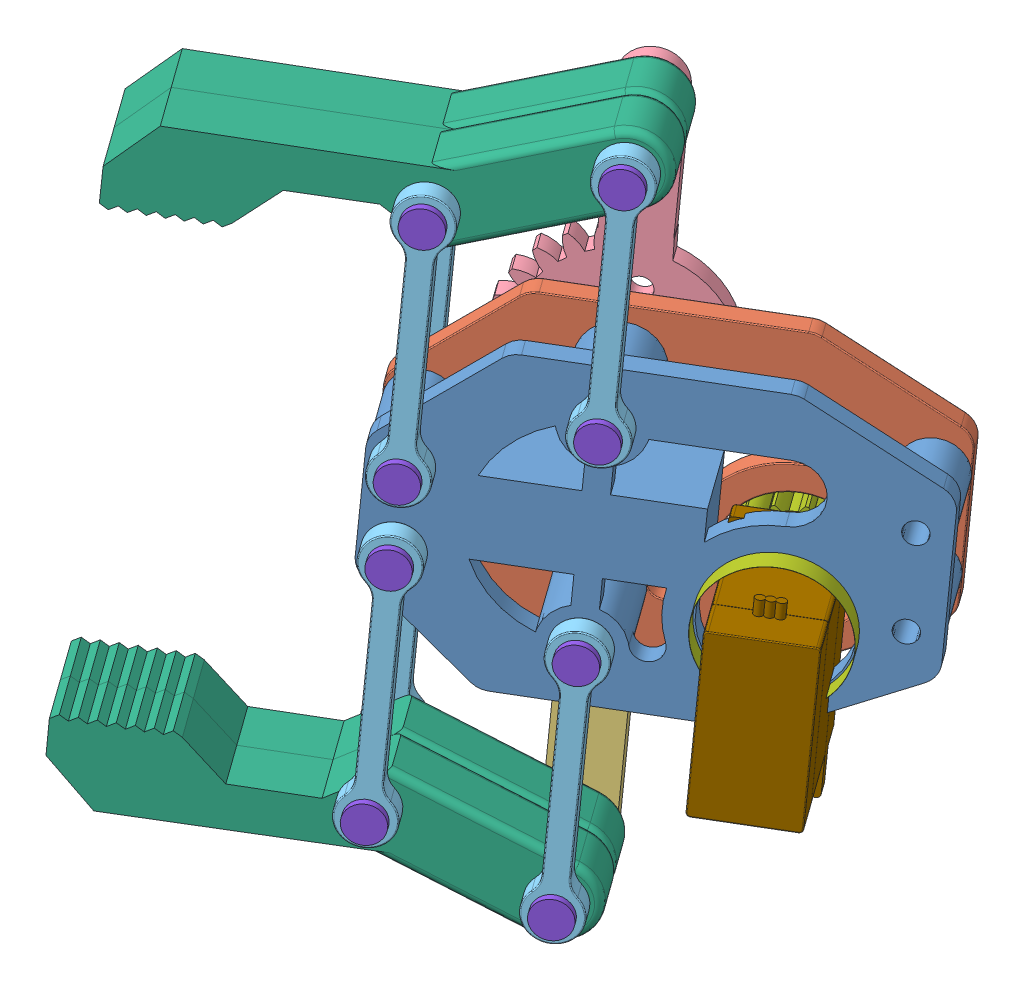
SolidWorks assembly Assemfinal, configuration Default. Lengths in mm.
Overall size (86.17 122.69 75.36).
24 component instances, 9 part files, 63 mates.
Components (placement in the parent):
- Part3-3-3: Part3-3 [Default] at (33.202 8.5379 122.0987) x (-0.009075 -0.994141 0.10771) z (-0.596574 -0.081063 -0.798454) size (41 62 13)
- Part3-3_g-1: Part3-3_g [Default] at (25.536 7.4962 111.8386) x (-0.009075 -0.994141 0.10771) z (-0.596574 -0.081063 -0.798454) size (41 62 3.03)
- part4-4-1: part4-4 [Default] at (-6.5503 -3.4794 133.1692) x (-0.596574 -0.081063 -0.798454) z (0.009075 0.994141 -0.10771) size (3 29.07 49.54)
- part5-5-1: part5-5 [Default] at (-8.095 23.1193 127.8657) x (0.596574 0.081063 0.798454) z (-0.113746 -0.976303 0.184105) size (3 26.63 49.27)
- Part2-2-1: Part2-2 [Default] at (-23.3572 47.3054 138.6922) x (-0.00933 -0.994118 0.107899) z (0.596574 0.081063 0.798454) size (38 7 3)
- Part1-1-1: Part1-1 [Default] at (-1.2513 54.8293 133.3096) x (-0.747201 -0.306991 0.589447) z (-0.596574 -0.081063 -0.798454) size (60.44 20.84 8)
- Part2-2-2: Part2-2 [Default] at (-24.015 -24.7496 146.499) x (0.00882 0.994164 -0.107522) z (0.596574 0.081063 0.798454) size (38 7 3)
- Part1-1-2: Part1-1 [Default] at (-6.8316 -34.2977 136.5082) x (-0.740386 0.439535 0.508564) z (0.596574 0.081063 0.798454) size (60.44 20.84 8)
- Part1-1-3: Part1-1 [Default] at (3.5213 55.4778 139.6973) x (-0.747201 -0.306991 0.589447) z (-0.596574 -0.081063 -0.798454) size (60.44 20.84 8)
- Part1-1-4: Part1-1 [Default] at (-2.059 -33.6492 142.8959) x (-0.740386 0.439535 0.508564) z (0.596574 0.081063 0.798454) size (60.44 20.84 8)
- Part2-2-3: Part2-2 [Default] at (-12.7695 -23.2215 161.5498) x (0.00882 0.994164 -0.107522) z (0.596574 0.081063 0.798454) size (38 7 3)
- Part2-2-4: Part2-2 [Default] at (-12.1118 48.8335 153.743) x (-0.00933 -0.994118 0.107899) z (0.596574 0.081063 0.798454) size (38 7 3)
- Part2-2-5: Part2-2 [Default] at (3.519 -32.8913 150.3614) x (0.009075 0.994141 -0.10771) z (0.596574 0.081063 0.798454) size (38 7 3)
- Part2-2-6: Part2-2 [Default] at (4.3266 55.5873 140.7752) x (-0.009075 -0.994141 0.10771) z (0.596574 0.081063 0.798454) size (38 7 3)
- part8-8-1: part8-8 [Default] at (13.0443 1.5296 125.347) x (0.596574 0.081063 0.798454) z (0.364182 -0.913901 -0.179319) size (23 17.5 17.5)
- Part6-6-1: Part6-6 [Default] at (-9.0261 -3.8158 129.8556) x (0.670786 -0.596574 -0.440619) z (-0.440619 -0.798454 0.410276) size (5 24 5)
- Part6-6-2: Part6-6 [Default] at (-25.5064 -24.9522 144.5028) x (0.670786 -0.596574 -0.440619) z (-0.440619 -0.798454 0.410276) size (5 24 5)
- Part6-6-3: Part6-6 [Default] at (-9.3074 -34.6341 133.1947) x (0.670786 -0.596574 -0.440619) z (-0.440619 -0.798454 0.410276) size (5 24 5)
- Part6-6-4: Part6-6 [Default] at (-25.233 5.8669 141.1697) x (0.670786 -0.596574 -0.440619) z (-0.440619 -0.798454 0.410276) size (5 24 5)
- Part6-6-5: Part6-6 [Default] at (-24.9381 47.0906 136.5763) x (0.670786 -0.596574 -0.440619) z (-0.440619 -0.798454 0.410276) size (5 24 5)
- Part6-6-6: Part6-6 [Default] at (-8.4997 53.8444 123.6084) x (0.670786 -0.596574 -0.440619) z (-0.440619 -0.798454 0.410276) size (5 24 5)
- Part6-6-7: Part6-6 [Default] at (-8.781 23.026 126.9474) x (0.670786 -0.596574 -0.440619) z (-0.440619 -0.798454 0.410276) size (5 24 5)
- Part6-6-8: Part6-6 [Default] at (-25.1379 16.2851 140.0409) x (0.670786 -0.596574 -0.440619) z (-0.440619 -0.798454 0.410276) size (5 24 5)
- microservoSG90-1: microservoSG90 [Default] at (27.0771 -1.6274 144.7399) x (-0.009075 -0.994141 0.10771) z (0.802507 -0.071503 -0.592343) size (32.3 29.8 12.5)
Mates (geometry in assembly coordinates):
- Coincident7: coincident anti-aligned: circle of Part3-3-3; circle of Part3-3_g-1
- Concentric3: concentric aligned: circle of Part3-3-3; circle of Part3-3_g-1
- Concentric6: concentric aligned: cylinder of Part3-3_g-1 through (-6.5503 -3.4794 133.1692) axis (0.596574 0.081063 0.798454) radius 1.5; cylinder of part4-4-1 through (-36.379 -7.5325 93.2465) axis (0.596574 0.081063 0.798454) radius 1.5
- Coincident11: coincident anti-aligned: plane of Part3-3_g-1 through (23.7463 7.253 109.4432) normal (-0.596574 -0.081063 -0.798454); plane of part4-4-1 through (-6.5503 -3.4794 133.1692) normal (0.596574 0.081063 0.798454)
- Concentric7: concentric anti-aligned: cylinder of Part3-3-3 through (1.3607 24.4041 140.5212) axis (0.596574 0.081063 0.798454) radius 1.5; cylinder of part5-5-1 through (21.7338 27.1724 167.7884) axis (-0.596574 -0.081063 -0.798454) radius 1.5
- Coincident12: coincident anti-aligned: plane of Part3-3_g-1 through (23.7463 7.253 109.4432) normal (-0.596574 -0.081063 -0.798454); plane of part5-5-1 through (-6.3053 23.3625 130.261) normal (0.596574 0.081063 0.798454)
- Concentric8: concentric anti-aligned: cylinder of Part3-3_g-1 through (-22.7516 16.6094 143.2347) axis (0.596574 0.081063 0.798454) radius 1.5; cylinder of Part2-2-1 through (-22.7516 16.6094 143.2347) axis (-0.596574 -0.081063 -0.798454) radius 1.5
- Coincident13: coincident anti-aligned: plane of Part3-3_g-1 through (23.7463 7.253 109.4432) normal (-0.596574 -0.081063 -0.798454); plane of Part2-2-1 through (-22.4623 47.427 139.8898) normal (0.596574 0.081063 0.798454)
- Concentric9: concentric anti-aligned: cylinder of part5-5-1 through (-6.0239 54.1808 126.922) axis (-0.596574 -0.081063 -0.798454) radius 1.5; cylinder of Part1-1-1 through (-6.0239 54.1808 126.922) axis (0.596574 0.081063 0.798454) radius 1.5
- Coincident14: coincident anti-aligned: plane of part5-5-1 through (-6.3053 23.3625 130.261) normal (0.596574 0.081063 0.798454); plane of Part1-1-1 through (-6.0239 54.1808 126.922) normal (-0.596574 -0.081063 -0.798454)
- Concentric10: concentric anti-aligned: cylinder of Part2-2-1 through (-22.4623 47.427 139.8898) axis (-0.596574 -0.081063 -0.798454) radius 1.5; cylinder of Part1-1-1 through (-22.4623 47.427 139.8898) axis (0.596574 0.081063 0.798454) radius 1.5
- Concentric11: concentric anti-aligned: cylinder of Part3-3_g-1 through (-22.8467 6.1911 144.3635) axis (0.596574 0.081063 0.798454) radius 1.5; cylinder of Part2-2-2 through (-22.8467 6.1911 144.3635) axis (-0.596574 -0.081063 -0.798454) radius 1.5
- Coincident15: coincident anti-aligned: plane of Part3-3_g-1 through (23.7463 7.253 109.4432) normal (-0.596574 -0.081063 -0.798454); plane of Part2-2-2 through (-23.1201 -24.628 147.6967) normal (0.596574 0.081063 0.798454)
- Concentric14: concentric anti-aligned: cylinder of part4-4-1 through (-8.6213 -34.5409 134.1129) axis (0.596574 0.081063 0.798454) radius 1.5; cylinder of Part1-1-2 through (-2.059 -33.6492 142.8959) axis (-0.596574 -0.081063 -0.798454) radius 1.5
- Coincident17: coincident anti-aligned: plane of part4-4-1 through (-6.5503 -3.4794 133.1692) normal (0.596574 0.081063 0.798454); plane of Part1-1-2 through (-6.8316 -34.2977 136.5082) normal (-0.596574 -0.081063 -0.798454)
- Concentric16: concentric aligned: cylinder of Part2-2-2 through (-23.1201 -24.628 147.6967) axis (-0.596574 -0.081063 -0.798454) radius 1.5; cylinder of Part1-1-2 through (-18.3475 -23.9795 154.0843) axis (-0.596574 -0.081063 -0.798454) radius 1.5
- Coincident18: coincident anti-aligned: plane of Part1-1-1 through (-1.2513 54.8293 133.3096) normal (0.596574 0.081063 0.798454); plane of Part1-1-3 through (-1.2513 54.8293 133.3096) normal (-0.596574 -0.081063 -0.798454)
- Concentric17: concentric aligned: cylinder of Part1-1-1 through (-6.0239 54.1808 126.922) axis (0.596574 0.081063 0.798454) radius 1.5; cylinder of Part1-1-3 through (-1.2513 54.8293 133.3096) axis (0.596574 0.081063 0.798454) radius 1.5
- Concentric18: concentric aligned: cylinder of Part1-1-1 through (-22.4623 47.427 139.8898) axis (0.596574 0.081063 0.798454) radius 1.5; cylinder of Part1-1-3 through (-17.6898 48.0755 146.2775) axis (0.596574 0.081063 0.798454) radius 1.5
- Concentric19: concentric aligned: cylinder of Part1-1-2 through (-2.059 -33.6492 142.8959) axis (-0.596574 -0.081063 -0.798454) radius 1.5; cylinder of Part1-1-4 through (2.7136 -33.0007 149.2835) axis (-0.596574 -0.081063 -0.798454) radius 1.5
- Coincident21: coincident anti-aligned: plane of Part1-1-2 through (-2.059 -33.6492 142.8959) normal (0.596574 0.081063 0.798454); plane of Part1-1-4 through (-2.059 -33.6492 142.8959) normal (-0.596574 -0.081063 -0.798454)
- Concentric20: concentric aligned: cylinder of Part1-1-2 through (-18.3475 -23.9795 154.0843) axis (-0.596574 -0.081063 -0.798454) radius 1.5; cylinder of Part1-1-4 through (-13.5749 -23.331 160.4719) axis (-0.596574 -0.081063 -0.798454) radius 1.5
- Concentric21: concentric anti-aligned: cylinder of Part3-3-3 through (-15.1807 7.2328 154.6236) axis (0.596574 0.081063 0.798454) radius 1.5; cylinder of Part2-2-3 through (-11.6013 7.7191 159.4143) axis (-0.596574 -0.081063 -0.798454) radius 1.5
- Coincident22: coincident anti-aligned: plane of Part3-3-3 through (33.202 8.5379 122.0987) normal (0.596574 0.081063 0.798454); plane of Part2-2-3 through (-13.6644 -23.3431 160.3521) normal (-0.596574 -0.081063 -0.798454)
- Concentric22: concentric aligned: cylinder of Part1-1-4 through (-13.5749 -23.331 160.4719) axis (-0.596574 -0.081063 -0.798454) radius 1.5; cylinder of Part2-2-3 through (-11.8747 -23.0999 162.7475) axis (-0.596574 -0.081063 -0.798454) radius 1.5
- Concentric23: concentric anti-aligned: cylinder of Part3-3-3 through (-15.0856 17.651 153.4948) axis (0.596574 0.081063 0.798454) radius 1.5; cylinder of Part2-2-4 through (-11.5062 18.1374 158.2856) axis (-0.596574 -0.081063 -0.798454) radius 1.5
- Coincident23: coincident anti-aligned: plane of Part3-3-3 through (33.202 8.5379 122.0987) normal (0.596574 0.081063 0.798454); plane of Part2-2-4 through (-13.0066 48.7119 152.5453) normal (-0.596574 -0.081063 -0.798454)
- Concentric24: concentric anti-aligned: cylinder of Part1-1-3 through (-17.6898 48.0755 146.2775) axis (0.596574 0.081063 0.798454) radius 1.5; cylinder of Part2-2-4 through (-11.2169 48.9551 154.9407) axis (-0.596574 -0.081063 -0.798454) radius 1.5
- Concentric25: concentric anti-aligned: cylinder of Part3-3-3 through (1.1157 -2.4377 143.4293) axis (0.596574 0.081063 0.798454) radius 1.5; cylinder of Part2-2-5 through (4.6951 -1.9513 148.2201) axis (-0.596574 -0.081063 -0.798454) radius 1.5
- Concentric26: concentric anti-aligned: cylinder of Part3-3-3 through (1.1157 -2.4377 143.4293) axis (0.596574 0.081063 0.798454) radius 1.5; cylinder of Part2-2-5 through (4.6951 -1.9513 148.2201) axis (-0.596574 -0.081063 -0.798454) radius 1.5
- Coincident24: coincident anti-aligned: plane of Part3-3-3 through (33.202 8.5379 122.0987) normal (0.596574 0.081063 0.798454); plane of Part2-2-5 through (2.6241 -33.0129 149.1637) normal (-0.596574 -0.081063 -0.798454)
- Concentric27: concentric aligned: cylinder of Part1-1-4 through (2.7136 -33.0007 149.2835) axis (-0.596574 -0.081063 -0.798454) radius 1.5; cylinder of Part2-2-5 through (4.4138 -32.7697 151.5591) axis (-0.596574 -0.081063 -0.798454) radius 1.5
- Concentric28: concentric anti-aligned: cylinder of Part1-1-3 through (-1.2513 54.8293 133.3096) axis (0.596574 0.081063 0.798454) radius 1.5; cylinder of Part2-2-6 through (5.2215 55.7089 141.9729) axis (-0.596574 -0.081063 -0.798454) radius 1.5
- Concentric29: concentric anti-aligned: cylinder of Part3-3-3 through (1.3607 24.4041 140.5212) axis (0.596574 0.081063 0.798454) radius 1.5; cylinder of Part2-2-6 through (4.9402 24.8905 145.3119) axis (-0.596574 -0.081063 -0.798454) radius 1.5
- Coincident25: coincident anti-aligned: plane of Part3-3-3 through (33.202 8.5379 122.0987) normal (0.596574 0.081063 0.798454); plane of Part2-2-6 through (3.4318 55.4657 139.5775) normal (-0.596574 -0.081063 -0.798454)
- Concentric30: concentric anti-aligned: cylinder of Part3-3-3 through (17.2203 2.0971 130.9362) axis (0.596574 0.081063 0.798454) radius 8.5; cylinder of part8-8-1 through (20.7997 2.5835 135.7269) axis (-0.596574 -0.081063 -0.798454) radius 8.75
- Coincident26: coincident anti-aligned: plane of Part3-3-3 through (33.202 8.5379 122.0987) normal (0.596574 0.081063 0.798454); plane of part8-8-1 through (19.01 2.3403 133.3316) normal (-0.596574 -0.081063 -0.798454)
- LimitAngle1: limit planar angle = 1.570796 rad anti-aligned: plane of part5-5-1 through (-3.0952 23.0764 127.8917) normal (0.802507 -0.071503 -0.592343); plane of Part3-3_g-1 through (-14.5075 31.0579 135.6082) normal (0.009075 0.994141 -0.10771)
- GearMate1: gear = 1 : 1 mm: cylinder of part4-4-1 through (-8.34 -3.7225 130.7738) axis (0.596574 0.081063 0.798454) radius 12.0927; cylinder of part5-5-1 through (-6.3053 23.3625 130.261) axis (-0.596574 -0.081063 -0.798454) radius 12.0927
- Concentric32: concentric aligned: cylinder of Part3-3-3 through (1.1157 -2.4377 143.4293) axis (0.596574 0.081063 0.798454) radius 1.5; cylinder of part4-4-1 through (-36.379 -7.5325 93.2465) axis (0.596574 0.081063 0.798454) radius 1.5
- GearMate2: gear = 13 : 24 mm: cylinder of part4-4-1 through (-8.34 -3.7225 130.7738) axis (0.596574 0.081063 0.798454) radius 12.0927; cylinder of part8-8-1 through (13.0443 1.5296 125.347) axis (0.596574 0.081063 0.798454) radius 5.249
- Concentric34: concentric anti-aligned: cylinder of Part3-3-3 through (1.1157 -2.4377 143.4293) axis (0.596574 0.081063 0.798454) radius 1.5; cylinder of Part6-6-1 through (-9.0261 -3.8158 129.8556) axis (-0.596574 -0.081063 -0.798454) radius 1.5
- Coincident31: coincident anti-aligned: plane of Part2-2-5 through (4.4138 -32.7697 151.5591) normal (0.596574 0.081063 0.798454); plane of Part6-6-1 through (3.0182 -0.4599 149.3216) normal (-0.596574 -0.081063 -0.798454)
- Concentric35: concentric aligned: cylinder of Part1-1-2 through (-18.3475 -23.9795 154.0843) axis (-0.596574 -0.081063 -0.798454) radius 1.5; cylinder of Part6-6-2 through (-25.5064 -24.9522 144.5028) axis (-0.596574 -0.081063 -0.798454) radius 1.5
- Coincident32: coincident anti-aligned: plane of Part2-2-2 through (-24.9098 -24.8711 145.3013) normal (-0.596574 -0.081063 -0.798454); plane of Part6-6-2 through (-25.916 -23.9763 145.9622) normal (0.596574 0.081063 0.798454)
- Concentric36: concentric aligned: cylinder of Part1-1-2 through (-2.059 -33.6492 142.8959) axis (-0.596574 -0.081063 -0.798454) radius 1.5; cylinder of Part6-6-3 through (-9.3074 -34.6341 133.1947) axis (-0.596574 -0.081063 -0.798454) radius 1.5
- Coincident33: coincident anti-aligned: plane of Part2-2-5 through (4.4138 -32.7697 151.5591) normal (0.596574 0.081063 0.798454); plane of Part6-6-3 through (2.7368 -31.2782 152.6606) normal (-0.596574 -0.081063 -0.798454)
- Concentric37: concentric anti-aligned: cylinder of Part3-3_g-1 through (-22.8467 6.1911 144.3635) axis (0.596574 0.081063 0.798454) radius 1.5; cylinder of Part6-6-4 through (-25.233 5.8669 141.1697) axis (-0.596574 -0.081063 -0.798454) radius 1.5
- Coincident34: coincident anti-aligned: plane of Part2-2-2 through (-24.9098 -24.8711 145.3013) normal (-0.596574 -0.081063 -0.798454); plane of Part6-6-4 through (-25.6426 6.8428 142.629) normal (0.596574 0.081063 0.798454)
- Concentric38: concentric aligned: cylinder of part5-5-1 through (-6.0239 54.1808 126.922) axis (-0.596574 -0.081063 -0.798454) radius 1.5; cylinder of Part6-6-6 through (-8.4997 53.8444 123.6084) axis (-0.596574 -0.081063 -0.798454) radius 1.5
- Coincident35: coincident anti-aligned: plane of Part2-2-6 through (5.2215 55.7089 141.9729) normal (0.596574 0.081063 0.798454); plane of Part6-6-6 through (3.5445 57.2003 143.0744) normal (-0.596574 -0.081063 -0.798454)
- Concentric39: concentric anti-aligned: cylinder of Part1-1-1 through (-22.4623 47.427 139.8898) axis (0.596574 0.081063 0.798454) radius 1.5; cylinder of Part6-6-5 through (-24.9381 47.0906 136.5763) axis (-0.596574 -0.081063 -0.798454) radius 1.5
- Coincident36: coincident anti-aligned: plane of Part2-2-4 through (-11.2169 48.9551 154.9407) normal (0.596574 0.081063 0.798454); plane of Part6-6-5 through (-12.8939 50.4465 156.0422) normal (-0.596574 -0.081063 -0.798454)
- Concentric40: concentric anti-aligned: cylinder of Part3-3_g-1 through (-6.3053 23.3625 130.261) axis (0.596574 0.081063 0.798454) radius 1.5; cylinder of Part6-6-7 through (-8.781 23.026 126.9474) axis (-0.596574 -0.081063 -0.798454) radius 1.5
- Coincident37: coincident anti-aligned: plane of Part2-2-6 through (5.2215 55.7089 141.9729) normal (0.596574 0.081063 0.798454); plane of Part6-6-7 through (3.2632 26.3819 146.4134) normal (-0.596574 -0.081063 -0.798454)
- Concentric41: concentric aligned: cylinder of Part2-2-1 through (-22.7516 16.6094 143.2347) axis (-0.596574 -0.081063 -0.798454) radius 1.5; cylinder of Part6-6-8 through (-25.1379 16.2851 140.0409) axis (-0.596574 -0.081063 -0.798454) radius 1.5
- Coincident38: coincident anti-aligned: plane of Part2-2-1 through (-24.2521 47.1838 137.4945) normal (-0.596574 -0.081063 -0.798454); plane of Part6-6-8 through (-25.5475 17.261 141.5003) normal (0.596574 0.081063 0.798454)
- Concentric45: concentric anti-aligned: circle of Part3-3_g-1; circle of Hinge-1/Half Hinge-1
- Coincident39: coincident anti-aligned: plane of Part3-3_g-1 through (23.7463 7.253 109.4432) normal (-0.596574 -0.081063 -0.798454); plane of Hinge-1/Half Hinge-1 through (-7.4651 11.6828 110.9699) normal (0.596574 0.081063 0.798454)
- Parallel1: parallel aligned: plane of Part3-3_g-1 through (-26.0817 3.7432 147.029) normal (-0.802507 0.071503 0.592343); plane of Hinge-1/Half Hinge-1 through (-19.5028 12.7462 119.856) normal (-0.802512 0.07089 0.592409)
- Concentric46: concentric aligned: circle of part8-8-1; circle of microservoSG90-1
- Parallel2: parallel aligned: plane of Part3-3-3 through (31.5121 19.2303 118.5185) normal (0.802507 -0.071503 -0.592343); plane of microservoSG90-1 through (22.8487 7.8985 127.3943) normal (0.802507 -0.071503 -0.592343)
- Coincident41: coincident anti-aligned: plane of Part3-3-3 through (31.4122 8.2947 119.7033) normal (-0.596574 -0.081063 -0.798454); plane of microservoSG90-1 through (17.0447 -17.1395 133.0204) normal (0.596574 0.081063 0.798454)
